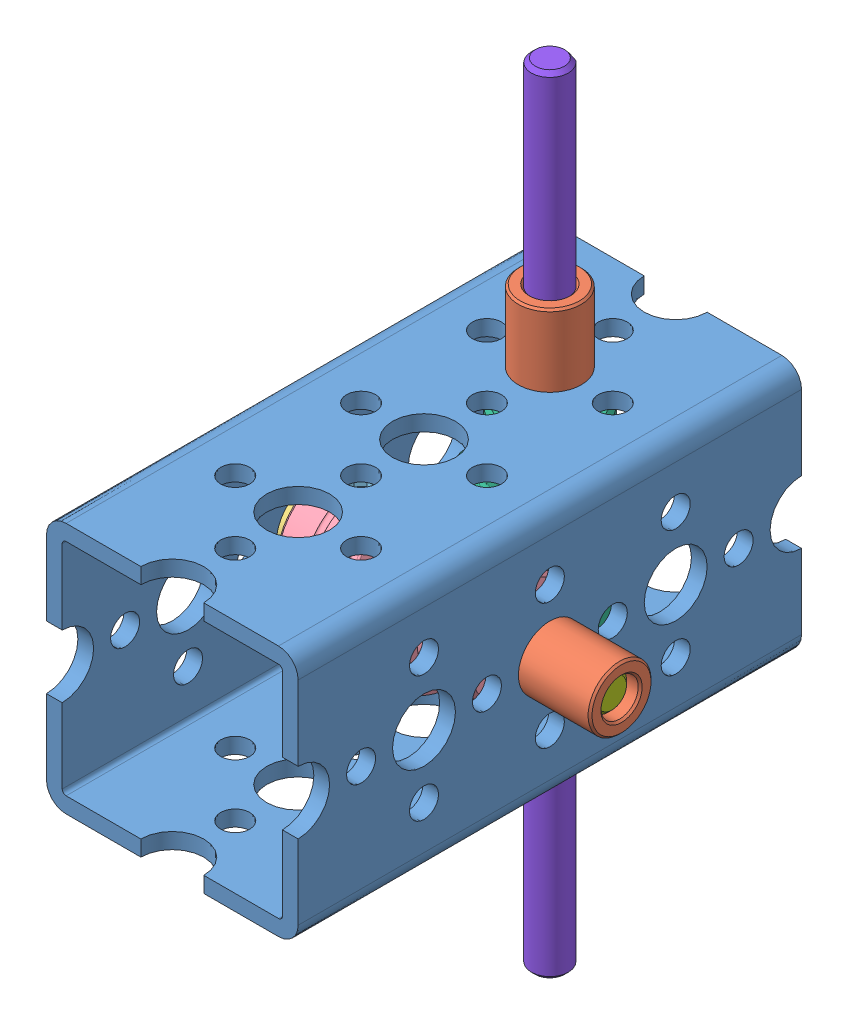
SolidWorks assembly Pitsco Education-739375, configuration Default. Lengths in mm.
Overall size (41.11 100 68.64).
15 component instances, 8 part files, 18 mates.
Components (placement in the parent):
- Pitsco Education-739375_X108111-1: Pitsco Education-739375_X108111 [Default] at (73.0758 -22.2585 -434.5216) size (32 32 64)
- Pitsco Education-739375_739091-9: Pitsco Education-739375_739091 [Default] at (85.4758 -22.2585 -434.5216) x (0 -0.995963 0.089765) z (0 0.089765 0.995963) size (9.56 12.71 9.56)
- Pitsco Education-739375_739091-11: Pitsco Education-739375_739091 [Default] at (73.0758 -34.6585 -450.5216) x (-0.995963 0 0.089765) z (0.089765 0 0.995963) size (9.56 12.71 9.56)
- Pitsco Education-739375_739091-12: Pitsco Education-739375_739091 [Default] at (73.0758 -9.8585 -450.5216) x (0.995963 0 0.089765) z (-0.089765 0 0.995963) size (9.56 12.71 9.56)
- Pitsco Education-739375_X108112-1: Pitsco Education-739375_X108112 [Default] at (60.6758 -22.2585 -434.5216) x (0 0.552568 -0.833468) z (0 0.833468 0.552568) size (9.56 3.6 9.56)
- Pitsco Education-739375_X108002-1: Pitsco Education-739375_X108002 [Default] at (72.7758 -22.2585 -434.5216) x (0 0 -1) z (1 0 0) size (20.24 20.26 24.6)
  - Pitsco Education-739375_X108105-1: Pitsco Education-739375_X108105 [4 to 1 with 16mm CC RV C] at (0 0 0.3) size (20.24 20.26 24.6)
  - Pitsco Education-739375_X108114-1: Pitsco Education-739375_X108114 [X108114] at (0 5.1532 -7.75) x (0.283386 0 0.959006) z (0 1 0) size (4.17 4.28 4.88)
  - Pitsco Education-739375_X108114-2: Pitsco Education-739375_X108114 [X108114] at (0 4.5582 8.25) x (0.283386 0 0.959006) z (0 1 0) size (4.17 4.28 4.88)
- Pitsco Education-739375_X108003-1: Pitsco Education-739375_X108003 [Default] at (73.0758 -21.8085 -450.5216) x (1 0 0) z (0 1 0) size (19.18 35.11 24.6)
  - Pitsco Education-739375_X108107-1: Pitsco Education-739375_X108107 [4 to 1 with 16mm CC RV C] at (0 0 -0.35) size (19.18 19.18 24.6)
  - Pitsco Education-739375_X108114-1: Pitsco Education-739375_X108114 [X108114] at (0 4.5582 -8.35) x (0.994498 0 0.104752) z (0 1 0) size (4.17 4.28 4.88)
  - Pitsco Education-739375_X108114-2: Pitsco Education-739375_X108114 [X108114] at (0 4.5582 7.65) x (0.994498 0 0.104752) z (0 1 0) size (4.17 4.28 4.88)
- Pitsco Education-739375_X108127-1: Pitsco Education-739375_X108127 [Default] at (84.4758 -22.2585 -434.5216) x (0 0 -1) z (0 -1 0) size (4.7 25 4.25)
- Pitsco Education-739375_739088-2: Pitsco Education-739375_739088 [Default] at (73.0758 -22.2585 -450.5216) size (4.7 100 4.22)
Mates (geometry in assembly coordinates):
- Coincident237: coincident anti-aligned: plane of Pitsco Education-739375_X108111-1 through (87.0758 -8.7585 -402.5216) normal (-1 0 0); plane of Pitsco Education-739375_739091-9 through (87.0758 -18.2746 -434.8807) normal (1 0 0)
- Concentric209: concentric anti-aligned: cylinder of Pitsco Education-739375_X108111-1 through (57.0758 -22.2585 -434.5216) axis (1 0 0) radius 4; cylinder of Pitsco Education-739375_739091-9 through (85.4758 -22.2585 -434.5216) axis (-1 0 0) radius 4
- Coincident239: coincident anti-aligned: plane of Pitsco Education-739375_X108111-1 through (59.5758 -8.2585 -402.5216) normal (0 -1 0); plane of Pitsco Education-739375_739091-12 through (69.092 -8.2585 -450.8807) normal (0 1 0)
- Concentric211: concentric anti-aligned: cylinder of Pitsco Education-739375_X108111-1 through (73.0758 -38.2585 -450.5216) axis (0 1 0) radius 4; cylinder of Pitsco Education-739375_739091-12 through (73.0758 -9.8585 -450.5216) axis (0 -1 0) radius 4
- Coincident240: coincident anti-aligned: plane of Pitsco Education-739375_X108111-1 through (59.5758 -36.2585 -402.5216) normal (0 1 0); plane of Pitsco Education-739375_739091-11 through (77.0597 -36.2585 -450.8807) normal (0 -1 0)
- Concentric212: concentric aligned: cylinder of Pitsco Education-739375_X108111-1 through (73.0758 -38.2585 -450.5216) axis (0 1 0) radius 4; cylinder of Pitsco Education-739375_739091-11 through (73.0758 -34.6585 -450.5216) axis (0 1 0) radius 4
- Concentric232: concentric aligned: cylinder of Pitsco Education-739375_X108111-1 through (57.0758 -22.2585 -434.5216) axis (1 0 0) radius 4; cylinder of Pitsco Education-739375_X108112-1 through (60.6758 -22.2585 -434.5216) axis (1 0 0) radius 3.975
- Coincident261: coincident anti-aligned: plane of Pitsco Education-739375_X108111-1 through (59.0758 -8.7585 -402.5216) normal (1 0 0); plane of Pitsco Education-739375_X108112-1 through (59.0758 -24.4549 -431.2086) normal (-1 0 0)
- Distance2: distance = 0.15 mm anti-aligned: plane of Pitsco Education-739375_739091-9 through (85.4758 -17.4978 -434.9507) normal (-1 0 0); plane of Pitsco Education-739375_X108002-1/Pitsco Education-739375_X108105-1 through (85.3258 -12.9533 -434.5216) normal (1 0 0)
- Concentric331: concentric anti-aligned: cylinder of Pitsco Education-739375_739091-9 through (85.4758 -22.2585 -434.5216) axis (-1 0 0) radius 2.375; cylinder of Pitsco Education-739375_X108002-1/Pitsco Education-739375_X108105-1 through (73.0758 -22.2585 -434.5216) axis (1 0 0) radius 6.75
- Coincident364: coincident anti-aligned: plane of Pitsco Education-739375_739091-12 through (68.3151 -9.8585 -450.9507) normal (0 -1 0); plane of Pitsco Education-739375_X108003-1/Pitsco Education-739375_X108107-1 through (73.0758 -9.8585 -456.0216) normal (0 1 0)
- Concentric332: concentric anti-aligned: cylinder of Pitsco Education-739375_739091-12 through (73.0758 -9.8585 -450.5216) axis (0 -1 0) radius 2.375; cylinder of Pitsco Education-739375_X108003-1/Pitsco Education-739375_X108107-1 through (73.0758 -22.1585 -450.5216) axis (0 1 0) radius 6
- Concentric349: concentric anti-aligned: cylinder of Pitsco Education-739375_739091-9 through (85.4758 -22.2585 -434.5216) axis (-1 0 0) radius 2.375; cylinder of Pitsco Education-739375_X108127-1 through (96.9758 -22.2585 -434.5216) axis (1 0 0) radius 2.35
- Coincident377: coincident aligned: plane of Pitsco Education-739375_X108002-1/Pitsco Education-739375_X108105-1 through (71.9758 -22.2585 -432.1466) normal (-1 0 0); plane of Pitsco Education-739375_X108127-1 through (71.9758 -22.2585 -434.5216) normal (-1 0 0)
- Parallel18: parallel aligned: plane of Pitsco Education-739375_X108002-1/Pitsco Education-739375_X108114-2 through (81.0258 -15.651 -434.5216) normal (0 1 0); plane of Pitsco Education-739375_X108127-1 through (71.9758 -20.3585 -434.5216) normal (0 1 0)
- Concentric350: concentric aligned: cylinder of Pitsco Education-739375_739091-11 through (73.0758 -34.6585 -450.5216) axis (0 1 0) radius 4; cylinder of Pitsco Education-739375_739088-2 through (73.0758 27.7415 -450.5216) axis (0 1 0) radius 2.35
- Parallel20: parallel aligned: plane of Pitsco Education-739375_X108003-1/Pitsco Education-739375_X108114-2 through (73.0758 -14.1585 -457.1291) normal (0 0 -1); plane of Pitsco Education-739375_739088-2 through (73.0758 -72.2585 -452.3916) normal (0 0 -1)
- Parallel21: parallel aligned: plane of Pitsco Education-739375_X108111-1 through (59.5758 -35.7585 -466.5216) normal (0 0 -1); plane of Pitsco Education-739375_739088-2 through (73.0758 -72.2585 -452.3916) normal (0 0 -1)
